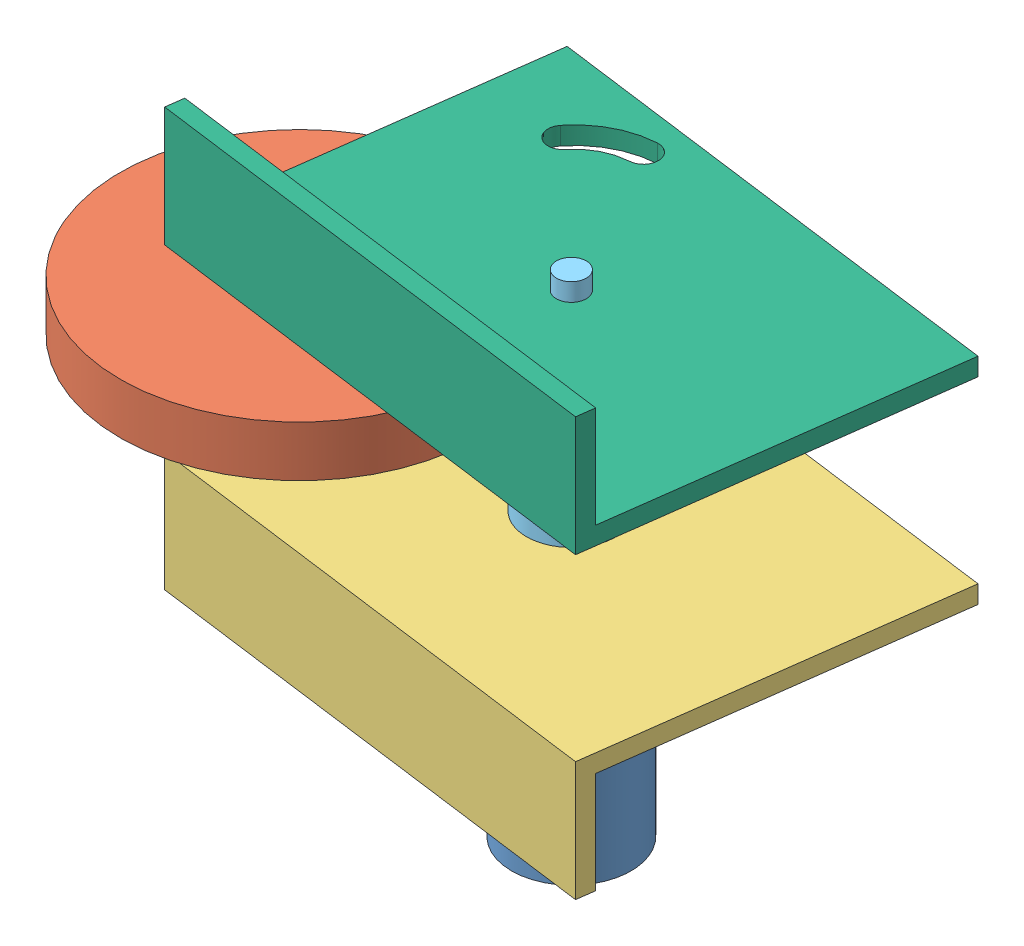
SolidWorks assembly Suspension prototype 2, configuration Default. Lengths in mm.
Overall size (120.1 96.2 84.33).
7 component instances, 7 part files, 14 mates.
Components (placement in the parent):
- DC motor-1: DC motor [Default] at (41.9341 21.4237 68.0483) size (20 61.2 20)
- wheel 50mm-1: wheel 50mm [Default] at (5.5756 80.6237 77.2304) x (-0.8979 0 0.440199) z (0 1 0) size (60 60 18.5)
- motor mount-2: motor mount [Default] at (-1.6661 67.6237 92.5234) x (0 -1 0) z (0.991303 0 0.1316) size (20 60 80)
- arm-1: arm [Default] at (4.376 94.1237 82.6903) x (-0.244856 0 -0.96956) z (0 -1 0) size (10 70 23)
- base-1: base [Default] at (13.7116 -39.8763 94.5648) x (0 -1 0) z (-0.1316 0 0.991303) (suppressed, hidden)
- shaft-1: shaft [Default] at (41.9341 68.6237 68.0483) x (-0.837169 0 -0.546944) z (0 1 0) size (15 15 35)
- Servo holder bracket-1: Servo holder bracket [Default] at (77.6382 97.6237 103.0514) x (0 1 0) z (-0.991303 0 -0.1316) size (20 60 80)
Mates (geometry in assembly coordinates):
- Parallel1: parallel aligned: plane of DC motor-1 through (41.9341 21.4237 68.0483) normal (0 -1 0); plane of wheel 50mm-1 through (5.5756 80.6237 77.2304) normal (0 -1 0)
- Concentric2: concentric anti-aligned: cylinder of DC motor-1 through (41.9341 82.6237 68.0483) axis (0 -1 0) radius 2; cylinder of rotation axis bracket-2 through (41.9341 47.6237 68.0483) axis (0 1 0) radius 2.5
- Coincident2: coincident anti-aligned: plane of DC motor-1 through (41.9341 64.6237 68.0483) normal (0 1 0); plane of rotation axis bracket-2 through (85.5342 64.6237 43.5732) normal (0 -1 0)
- Concentric4: concentric aligned: cylinder of wheel 50mm-1 through (5.5756 70.6237 77.2304) axis (0 1 0) radius 2.5; cylinder of arm-1 through (5.5756 71.1237 77.2304) axis (0 1 0) radius 2.5
- Distance1: distance = 2 mm anti-aligned: plane of rotation part-1 through (4.376 91.1237 82.6903) normal (0 -1 0); plane of wheel 50mm-1 through (5.5756 89.1237 77.2304) normal (0 1 0)
- Distance2: distance = 3 mm anti-aligned: plane of wheel 50mm-1 through (5.5756 70.6237 77.2304) normal (0 -1 0); plane of rotation axis bracket-2 through (77.6382 67.6237 103.0514) normal (0 1 0)
- Coincident10: coincident anti-aligned: plane of rotation axis bracket-2 through (77.6382 67.6237 103.0514) normal (-0.1316 0 0.991303); plane of base-1 through (13.7116 -39.8763 94.5648) normal (0.1316 0 -0.991303)
- Concentric5: concentric aligned: cylinder of DC motor-1 through (41.9341 82.6237 68.0483) axis (0 -1 0) radius 2; cylinder of shaft-1 through (41.9341 83.6237 68.0483) axis (0 -1 0) radius 2.5
- Distance5: distance = 1 mm anti-aligned: plane of shaft-1 through (41.9341 68.6237 68.0483) normal (0 -1 0); plane of rotation axis bracket-2 through (77.6382 67.6237 103.0514) normal (0 1 0)
- Concentric6: concentric anti-aligned: cylinder of arm-1 through (41.9341 74.1237 68.0483) axis (0 1 0) radius 2.5; cylinder of shaft-1 through (41.9341 103.6237 68.0483) axis (0 -1 0) radius 2.5
- Coincident13: coincident anti-aligned: plane of base-1 through (13.7116 -39.8763 94.5648) normal (0.1316 0 -0.991303); plane of Servo holder bracket-1 through (-1.6661 97.6237 92.5234) normal (-0.1316 0 0.991303)
- Concentric7: concentric aligned: cylinder of shaft-1 through (41.9341 103.6237 68.0483) axis (0 -1 0) radius 2.5; cylinder of Servo holder bracket-1 through (41.9341 117.6237 68.0483) axis (0 -1 0) radius 2.5
- Distance6: distance = 5 mm aligned: plane of base-1 through (53.3637 92.6237 99.8288) normal (0 -1 0); plane of Servo holder bracket-1 through (-1.6661 97.6237 92.5234) normal (0 -1 0)
- Distance7: distance = 30 mm anti-aligned: plane of rotation axis bracket-2 through (77.6382 67.6237 103.0514) normal (0 1 0); plane of Servo holder bracket-1 through (-1.6661 97.6237 92.5234) normal (0 -1 0)
